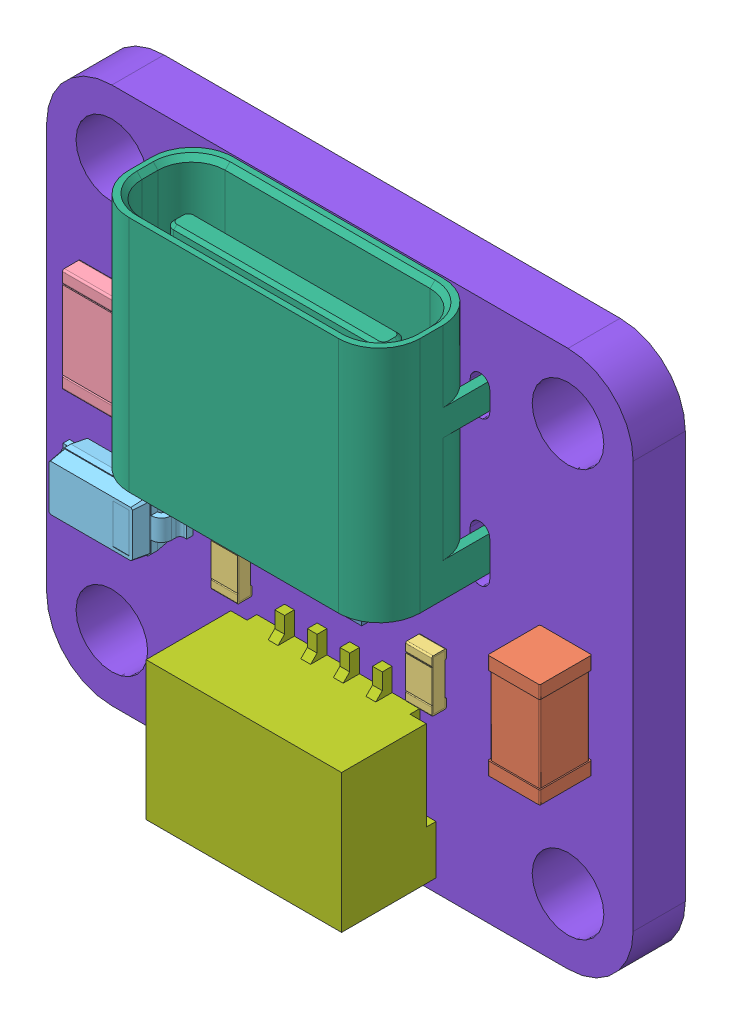
SolidWorks assembly Unified-Daughterboard, configuration Default. Lengths in mm.
Overall size (18 16.5 4.86).
18 component instances, 8 part files, 0 mates.
Components (placement in the parent):
- Unified-Daughterboard(2)^Unified-Daughterboard-1: Unified-Daughterboard(2)^Unified-Daughterboard [Default] at origin size (18 16.5 4.86) (virtual)
  - USON-10_2.5x1.0mm_P0.5mm^Unified-Daughterboard(2)_Unified-Daughterboard-1: USON-10_2.5x1.0mm_P0.5mm^Unified-Daughterboard(2)_Unified-Daughterboard [Default] at (75.0025 -66.0264 1.65) x (0 1 0) z (0 0 1) size (1 2.48 0.52) (virtual)
    - SOLID^USON-10_2.5x1.0mm_P0.5mm_Unified-Daughterboard(2)_Unified-Daughterboard-1: SOLID^USON-10_2.5x1.0mm_P0.5mm_Unified-Daughterboard(2)_Unified-Daughterboard [Default] at origin size (1 2.48 0.52) (virtual)
  - L_1206_3216Metric^Unified-Daughterboard(2)_Unified-Daughterboard-1: L_1206_3216Metric^Unified-Daughterboard(2)_Unified-Daughterboard [Default] at (81.9875 -65.874 1.65) x (0 1 0) z (0 0 1) size (3.2 1.6 1.6) (virtual)
    - SOLID-0^L_1206_3216Metric_Unified-Daughterboard(2)_Unified-Daughterboard-1: SOLID-0^L_1206_3216Metric_Unified-Daughterboard(2)_Unified-Daughterboard [Default] at origin size (3.2 1.6 1.6) (virtual)
  - R_0603_1608Metric^Unified-Daughterboard(2)_Unified-Daughterboard-1: R_0603_1608Metric^Unified-Daughterboard(2)_Unified-Daughterboard [Default] at (71.9545 -67.129 1.65) x (0 -1 0) z (0 0 1) size (1.6 0.8 0.45) (virtual)
    - SOLID-1^R_0603_1608Metric_Unified-Daughterboard(2)_Unified-Daughterboard-1: SOLID-1^R_0603_1608Metric_Unified-Daughterboard(2)_Unified-Daughterboard [Default] at origin size (1.6 0.8 0.45) (virtual)
  - R_1206_3216Metric^Unified-Daughterboard(2)_Unified-Daughterboard-1: R_1206_3216Metric^Unified-Daughterboard(2)_Unified-Daughterboard [Default] at (67.8905 -63.207 1.65) x (0 -1 0) z (0 0 1) size (3.2 1.6 0.55) (virtual)
    - SOLID-2^R_1206_3216Metric_Unified-Daughterboard(2)_Unified-Daughterboard-1: SOLID-2^R_1206_3216Metric_Unified-Daughterboard(2)_Unified-Daughterboard [Default] at origin size (3.2 1.6 0.55) (virtual)
  - D_SOD-123^Unified-Daughterboard(2)_Unified-Daughterboard-1: D_SOD-123^Unified-Daughterboard(2)_Unified-Daughterboard [Default] at (68.6525 -66.89 1.65) x (-1 0 0) z (0 0 1) size (3.8 1.6 1.25) (virtual)
    - SOLID-3^D_SOD-123_Unified-Daughterboard(2)_Unified-Daughterboard-1: SOLID-3^D_SOD-123_Unified-Daughterboard(2)_Unified-Daughterboard [Default] at origin size (3.8 1.6 1.25) (virtual)
  - HRO__TYPE-C-31-M-12^Unified-Daughterboard(2)_Unified-Daughterboard-1: HRO__TYPE-C-31-M-12^Unified-Daughterboard(2)_Unified-Daughterboard [Default] at (79.4725 -56.543 1.65) x (-1 0 0) z (0 1 0) size (8.94 4.21 7.9) (virtual)
    - SOLID-4^HRO__TYPE-C-31-M-12_Unified-Daughterboard(2)_Unified-Daughterboard-1: SOLID-4^HRO__TYPE-C-31-M-12_Unified-Daughterboard(2)_Unified-Daughterboard [Default] at origin size (8.94 4.21 7.9) (virtual)
  - JST-SR-4^Unified-Daughterboard(2)_Unified-Daughterboard-1: JST-SR-4^Unified-Daughterboard(2)_Unified-Daughterboard [Default] at (75.0045 -72.793 1.65) x (1 0 0) z (0 -1 0) size (6 2.9 4.95) (virtual)
    - SOLID-5^JST-SR-4_Unified-Daughterboard(2)_Unified-Daughterboard-1: SOLID-5^JST-SR-4_Unified-Daughterboard(2)_Unified-Daughterboard [Default] at origin size (6 2.9 4.95) (virtual)
  - R_0603_1608Metric^Unified-Daughterboard(2)_Unified-Daughterboard-2: R_0603_1608Metric^Unified-Daughterboard(2)_Unified-Daughterboard [Default] at (77.9235 -67.129 1.65) x (0 -1 0) z (0 0 1) size (1.6 0.8 0.45) (virtual)
    - SOLID-1^R_0603_1608Metric_Unified-Daughterboard(2)_Unified-Daughterboard-1: SOLID-1^R_0603_1608Metric_Unified-Daughterboard(2)_Unified-Daughterboard [Default] at origin size (1.6 0.8 0.45) (virtual)
  - Daughterboard^Unified-Daughterboard(2)_Unified-Daughterboard-1: Daughterboard^Unified-Daughterboard(2)_Unified-Daughterboard [Default] at origin size (18 16.5 1.6) (virtual)
